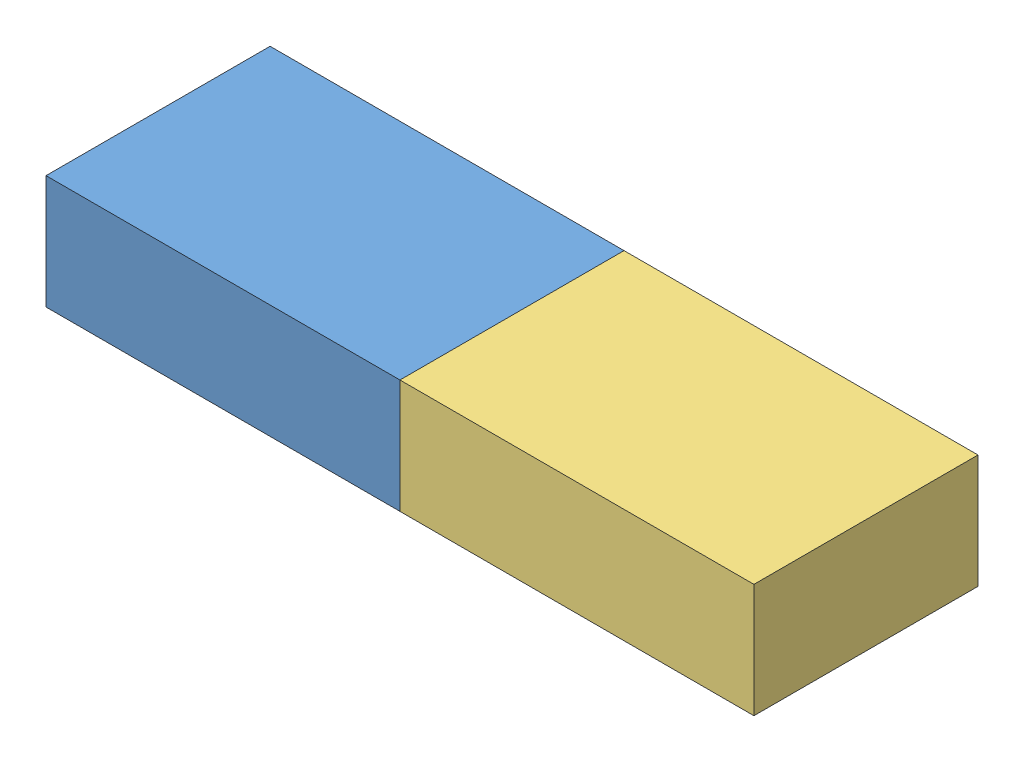
SolidWorks assembly fabisp, configuration Default. Lengths in mm.
Overall size (149.3 24 47.26).
4 component instances, 3 part files, 8 mates.
Components (placement in the parent):
- Tooling Split1[2]-1: Tooling Split1[2] [Default] at origin size (74.65 24 47.26)
- Parting Line1[1]-1: Parting Line1[1] [Default] at (74.65 9 -0.5202) x (1 0 0) z (0 0 -1) size (48 9 23)
- Tooling Split1[1]-1: Tooling Split1[1] [Default] at (74.65 9 -0.5202) x (1 0 0) z (0 0 -1) size (74.65 24 47.26)
- Parting Line1[1]-2: Parting Line1[1] [Default] at origin size (48 9 23)
Mates (geometry in assembly coordinates):
- Concentric3: concentric aligned: circle of Parting Line1[1]-1; circle of Tooling Split1[1]-1
- Coincident7: coincident anti-aligned: plane of Parting Line1[1]-1 through (45.65 5.675 -6.7202) normal (0 1 0); plane of Tooling Split1[1]-1 through (45.65 5.675 -6.7202) normal (0 -1 0)
- Concentric5: concentric aligned: circle of Parting Line1[1]-1; circle of Tooling Split1[1]-1
- Concentric6: concentric aligned: circle of Tooling Split1[2]-1; circle of Parting Line1[1]-2
- Coincident24: coincident aligned: line of Tooling Split1[2]-1 through (-29 5.675 5.836) axis (0 0 -1); line of Parting Line1[1]-2 through (-29 5.675 5.836) axis (0 0 -1)
- Coincident27: coincident anti-aligned: plane of Tooling Split1[2]-1 through (31.4402 -9.5 -23.8901) normal (1 0 0); plane of Tooling Split1[1]-1 through (31.4402 -9.5 -23.8901) normal (-1 0 0)
- Coincident28: coincident aligned: plane of Tooling Split1[2]-1 through (-43.2098 -9.5 -23.8901) normal (0 0 -1); plane of Tooling Split1[1]-1 through (31.4402 -9.5 -23.8901) normal (0 0 -1)
- Coincident29: coincident aligned: plane of Tooling Split1[2]-1 through (0 -9.5 0) normal (0 -1 0); plane of Tooling Split1[1]-1 through (74.65 -9.5 -0.5202) normal (0 -1 0)
